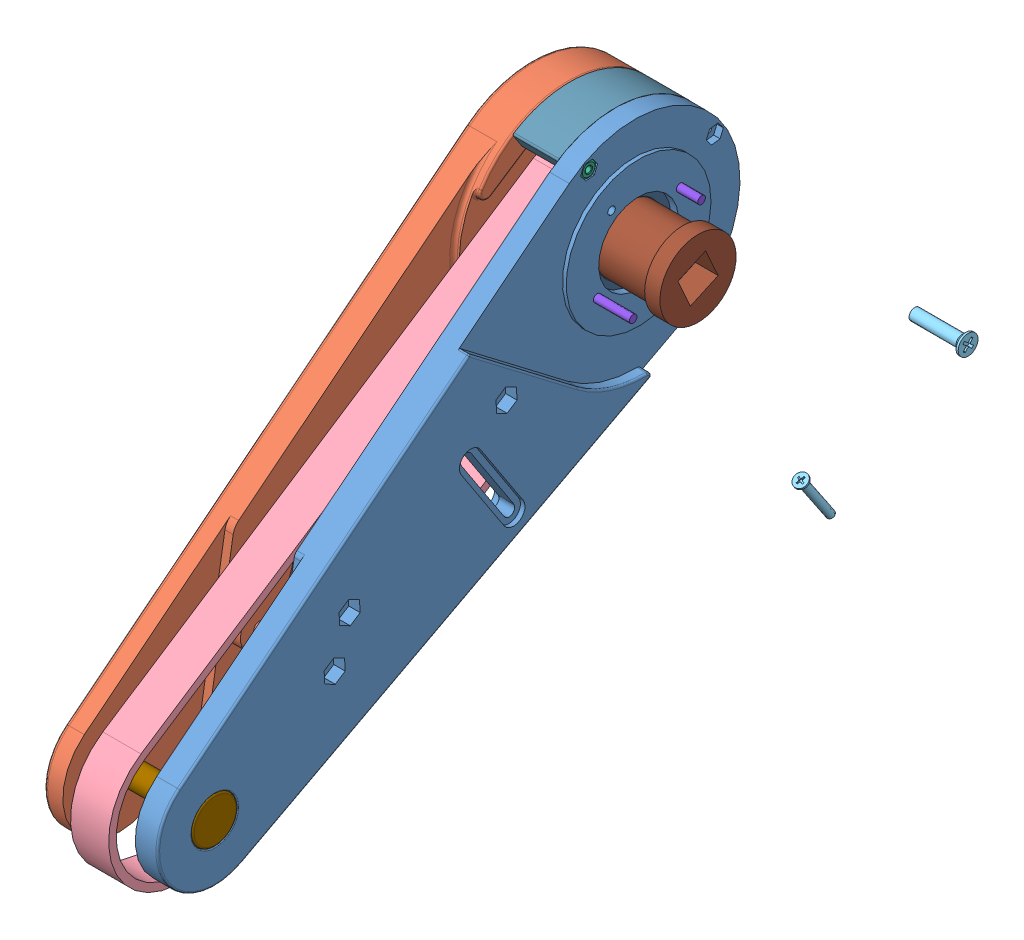
SolidWorks assembly LB_THIGH_LINK, configuration 默认. Lengths in mm.
Overall size (105.92 160 183.93).
22 component instances, 14 part files, 32 mates.
Components (placement in the parent):
- 大足-1: 大足 [默认] at (-90.65 -2.5888 118.152) x (0 -0.836771 -0.547553) z (1 0 0) size (55.2 177.6 19.75)
- 大足2-1: 大足2 [默认] at (-105.4 -2.5888 118.152) x (0 0.836771 0.547553) z (-1 0 0) size (55.62 177.6 10.15)
- 光杆同步轮-1: 光杆同步轮 [GearTrax] at (-100.2 -2.5888 118.152) x (0 0.683821 0.72965) z (1 0 0) size (35.45 35.52 10)
- 同步带-1: 同步带 [默认] at (-104.7637 -2.5888 118.152) x (0 -0.547553 0.836771) z (0 0.836771 0.547553) size (172.52 10 37.52)
- cross recessed countersunk head screws gb1-1: cross recessed countersunk head screws gb1 [GB_CROSS_SCREWS_TYPE4 M2X20-18.8  H type-N] at (-115.4358 19.4561 130.1533) x (1 0 0) z (0 -0.751747 -0.659452) size (20 3.5 3.5)
- hex nuts, style 1-grades ab gb-1: hex nuts, style 1-grades ab gb [GB_FASTENER_NUT_SNAB1 M2-N] at (-88.5 19.458 130.1497) x (0 0.147368 0.989082) z (1 0 0) size (4.62 4 1.6)
- 端盖-1: 端盖 [默认] at (-110.9 -2.4774 118.5694) x (0 0.786358 0.617771) z (0 -0.617771 0.786358) size (22 3 22)
- cross countersunk head screw_as-1: cross countersunk head screw_as [AS-NZS 1023 CC- M2 x 12-N] at (-113.7309 -2.4774 118.5694) x (1 0 0) z (0 -0.616412 0.787424) size (12 3.8 3.8)
- 字母钉-1: 字母钉 [默认] at (-100.85 -76.5085 231.1161) x (0 0.552917 0.833236) z (0 -0.833236 0.552917) size (12 30.6 12)
- 17-23-4轴承-1: 17-23-4轴承 [默认] at (-106.4 -2.4774 118.5694) x (0 -0.543433 0.839453) z (-1 0 0) size (23 23 4)
- 传动轴-1: 传动轴 [默认] at (-71.4 -2.4774 118.5694) x (0 0.413244 -0.910621) z (-1 0 0) size (20 20 39)
- 定位环_17_20_1-2mm-1: 定位环_17_20_1-2mm [默认] at (-106.4 -2.5888 118.152) x (0 0.552917 0.833236) z (0 0.833236 -0.552917) size (20 1.2 20)
- 定位环-1: 定位环 [默认] at (-95.2 -2.4774 118.5694) x (0 0.442477 0.89678) z (0 0.89678 -0.442477) size (20.4 1.65 20.4)
- 17-23-4轴承-2: 17-23-4轴承 [默认] at (-93.4 -2.4774 118.5694) x (0 0.817974 0.575255) z (1 0 0) size (23 23 4)
- cross countersunk head screw_as-2: cross countersunk head screw_as [AS-NZS 1023 CC- M2 x 16-N] at (-93.95 -13.4669 111.0338) x (1 0 0) z (0 -0.191574 -0.981478) size (16 3.8 3.8)
- cross countersunk head screw_as-3: cross countersunk head screw_as [AS-NZS 1023 CC- M2 x 12-N] at (-93.75 4.5293 107.274) x (1 0 0) z (0 0.833954 -0.551834) size (12 3.8 3.8)
- cross countersunk head screw_as-4: cross countersunk head screw_as [AS-NZS 1023 CC- M2 x 16-N] at (-93.95 -9.707 129.03) x (1 0 0) z (0 -0.191574 -0.981478) size (16 3.8 3.8)
- cross recessed countersunk head screws gb1-2: cross recessed countersunk head screws gb1 [GB_CROSS_SCREWS_TYPE4 M2X14-12.8  H type-N] at (-78.4 -68.8019 84.6359) x (0 -0.82919 -0.558967) z (0.946399 -0.180547 0.267829) size (14 3.5 3.5)
- cross recessed countersunk head screws gb1-3: cross recessed countersunk head screws gb1 [GB_CROSS_SCREWS_TYPE4 M3X14-12.35  H type-N] at (-10.45 7.9435 108.633) x (-1 0 0) z (0 0.749512 -0.661991) size (14 5.2 5.2)
- 支撑半环-1: 支撑半环 [默认] at (-105.4 -2.5888 118.152) x (0 -0.836727 -0.54762) z (0 -0.54762 0.836727) size (55.19 11.85 27.6)
- cross recessed countersunk head screws gb1-4: cross recessed countersunk head screws gb1 [GB_CROSS_SCREWS_TYPE4 M2X20-18.8  H type-N] at (-116.3706 11.1564 97.1501) x (1 0 0) z (0 0.970436 -0.241357) size (20 3.5 3.5)
- cross recessed countersunk head screws gb1-5: cross recessed countersunk head screws gb1 [GB_CROSS_SCREWS_TYPE4 M2X20-18.8  H type-N] at (-115.614 -22.4099 102.7528) x (1 0 0) z (0 -0.050336 -0.998732) size (20 3.5 3.5)
Mates (geometry in assembly coordinates):
- 同心571: concentric anti-aligned: cylinder of 大足-1 through (-9.5854 -2.5888 118.152) axis (-1 0 0) radius 27.6; cylinder of 光杆同步轮-1 through (-100.2 -2.5888 118.152) axis (1 0 0) radius 17.7614
- 同心580: concentric anti-aligned: cylinder of 大足2-1 through (-115.55 -76.5085 231.1161) axis (1 0 0) radius 15; cylinder of 同步带-1 through (-94.7637 -76.5085 231.1161) axis (-1 0 0) radius 16.76
- 同心581: concentric anti-aligned: cylinder of 大足2-1 through (-115.55 -2.5888 118.152) axis (1 0 0) radius 27.6; cylinder of 同步带-1 through (-94.7637 -2.5888 118.152) axis (-1 0 0) radius 18.76
- 同心584: concentric anti-aligned: cylinder of 大足2-1 through (-105.3675 19.4561 130.1533) axis (-1 0 0) radius 1; cylinder of cross recessed countersunk head screws gb1-1 through (-110.92 19.4561 130.1533) axis (1 0 0) radius 1
- 同心577: concentric anti-aligned: cylinder of 大足-1 through (-85.6123 19.458 130.1497) axis (-1 0 0) radius 0.81; cylinder of hex nuts, style 1-grades ab gb-1 through (-90.1 19.458 130.1497) axis (1 0 0) radius 0.7835
- 重合320: coincident anti-aligned: plane of 大足-1 through (-90.1 -2.5888 118.152) normal (1 0 0); plane of hex nuts, style 1-grades ab gb-1 through (-90.1 19.7984 132.4339) normal (-1 0 0)
- 同心595: concentric aligned: cylinder of 端盖-1 through (-110.9 -2.4774 118.5694) axis (-1 0 0) radius 1; cylinder of cross countersunk head screw_as-1 through (-113.7309 -2.4774 118.5694) axis (-1 0 0) radius 1
- 重合332: coincident aligned: plane of 端盖-1 through (-113.4 -2.4774 118.5694) normal (-1 0 0); circle of cross countersunk head screw_as-1
- 同心586: concentric anti-aligned: cylinder of 大足2-1 through (-111.25 -76.5085 231.1161) axis (-1 0 0) radius 3.48; cylinder of 字母钉-1 through (-115.15 -76.5085 231.1161) axis (1 0 0) radius 3
- 重合322: coincident anti-aligned: plane of 大足2-1 through (-115.15 -76.5085 231.1161) normal (-1 0 0); plane of 字母钉-1 through (-115.15 -76.5085 231.1161) normal (1 0 0)
- 重合321: coincident anti-aligned: plane of 17-23-4轴承-1 through (-106.4 -2.4774 118.5694) normal (1 0 0); plane of 大足2-1 through (-106.4 -2.5888 118.152) normal (-1 0 0)
- 重合331: coincident anti-aligned: plane of 17-23-4轴承-1 through (-110.4 -2.4774 118.5694) normal (-1 0 0); plane of 端盖-1 through (-110.4 -2.4774 118.5694) normal (1 0 0)
- 同心594: concentric anti-aligned: cylinder of 传动轴-1 through (-111.2284 -2.4774 118.5694) axis (1 0 0) radius 0.85; cylinder of 端盖-1 through (-110.9 -2.4774 118.5694) axis (-1 0 0) radius 1
- 同心647: concentric aligned: cylinder of 传动轴-1 through (-106.4 -2.4774 118.5694) axis (1 0 0) radius 8.5; cylinder of 17-23-4轴承-1 through (-110.4 -2.4774 118.5694) axis (1 0 0) radius 8.5
- 同心582: concentric anti-aligned: cylinder of 大足2-1 through (-115.55 -2.5888 118.152) axis (1 0 0) radius 27.6; cylinder of 定位环_17_20_1-2mm-1 through (-105.2 -2.5888 118.152) axis (-1 0 0) radius 8.6
- 重合329: coincident anti-aligned: plane of 光杆同步轮-1 through (-105.2 -0.8455 92.2271) normal (-1 0 0); plane of 定位环_17_20_1-2mm-1 through (-105.2 -2.5888 118.152) normal (1 0 0)
- 重合372: coincident anti-aligned: plane of 17-23-4轴承-1 through (-106.4 -2.4774 118.5694) normal (1 0 0); plane of 定位环_17_20_1-2mm-1 through (-106.4 -2.5888 118.152) normal (-1 0 0)
- 重合316: coincident anti-aligned: plane of 大足-1 through (-93.55 -2.5888 118.152) normal (-1 0 0); plane of 定位环-1 through (-93.55 -2.4774 118.5694) normal (1 0 0)
- 同心649: concentric anti-aligned: cylinder of 传动轴-1 through (-106.4 -2.4774 118.5694) axis (1 0 0) radius 8.5; circle of 定位环-1
- 重合315: coincident anti-aligned: plane of 大足-1 through (-89.4 -2.5888 118.152) normal (-1 0 0); plane of 17-23-4轴承-2 through (-89.4 -2.4774 118.5694) normal (1 0 0)
- 同心648: concentric anti-aligned: cylinder of 传动轴-1 through (-106.4 -2.4774 118.5694) axis (1 0 0) radius 8.5; cylinder of 17-23-4轴承-2 through (-89.4 -2.4774 118.5694) axis (-1 0 0) radius 8.5
- 同心573: concentric aligned: cylinder of 大足-1 through (-85.6123 -13.4669 111.0338) axis (-1 0 0) radius 1; cylinder of cross countersunk head screw_as-2 through (-93.95 -13.4669 111.0338) axis (-1 0 0) radius 1
- 距离50: distance = 0.4 mm aligned: plane of cross countersunk head screw_as-2 through (-93.95 -13.4669 111.0338) normal (-1 0 0); plane of 大足-1 through (-93.55 -2.5888 118.152) normal (-1 0 0)
- 同心572: concentric aligned: cylinder of 大足-1 through (-85.6123 4.5293 107.274) axis (-1 0 0) radius 1; cylinder of cross countersunk head screw_as-3 through (-93.75 4.5293 107.274) axis (-1 0 0) radius 1
- 距离49: distance = 0.2 mm aligned: plane of cross countersunk head screw_as-3 through (-93.75 4.5293 107.274) normal (-1 0 0); plane of 大足-1 through (-93.55 -2.5888 118.152) normal (-1 0 0)
- 同心574: concentric aligned: cylinder of 大足-1 through (-85.6123 -9.707 129.03) axis (-1 0 0) radius 1; cylinder of cross countersunk head screw_as-4 through (-93.95 -9.707 129.03) axis (-1 0 0) radius 1
- 距离51: distance = 0.4 mm aligned: plane of cross countersunk head screw_as-4 through (-93.95 -9.707 129.03) normal (-1 0 0); plane of 大足-1 through (-93.55 -2.5888 118.152) normal (-1 0 0)
- 重合317: coincident anti-aligned: plane of 大足-1 through (-93.55 -2.5888 118.152) normal (-1 0 0); plane of 支撑半环-1 through (-93.55 -2.5888 118.152) normal (1 0 0)
- 同心575: concentric anti-aligned: cylinder of 大足-1 through (-85.6123 -22.4099 102.7528) axis (-1 0 0) radius 0.81; cylinder of 支撑半环-1 through (-105.4 -22.4099 102.7528) axis (1 0 0) radius 1
- 同心579: concentric anti-aligned: cylinder of 大足2-1 through (-115.55 -2.5888 118.152) axis (1 0 0) radius 27.6; cylinder of 支撑半环-1 through (-93.55 -2.5888 118.152) axis (-1 0 0) radius 27.6
- 同心585: concentric anti-aligned: cylinder of 大足2-1 through (-105.3675 11.1564 97.1501) axis (-1 0 0) radius 1; cylinder of cross recessed countersunk head screws gb1-4 through (-111.8548 11.1564 97.1501) axis (1 0 0) radius 1
- 同心583: concentric anti-aligned: cylinder of 大足2-1 through (-105.3675 -22.4099 102.7528) axis (-1 0 0) radius 1; cylinder of cross recessed countersunk head screws gb1-5 through (-111.0981 -22.4099 102.7528) axis (1 0 0) radius 1
